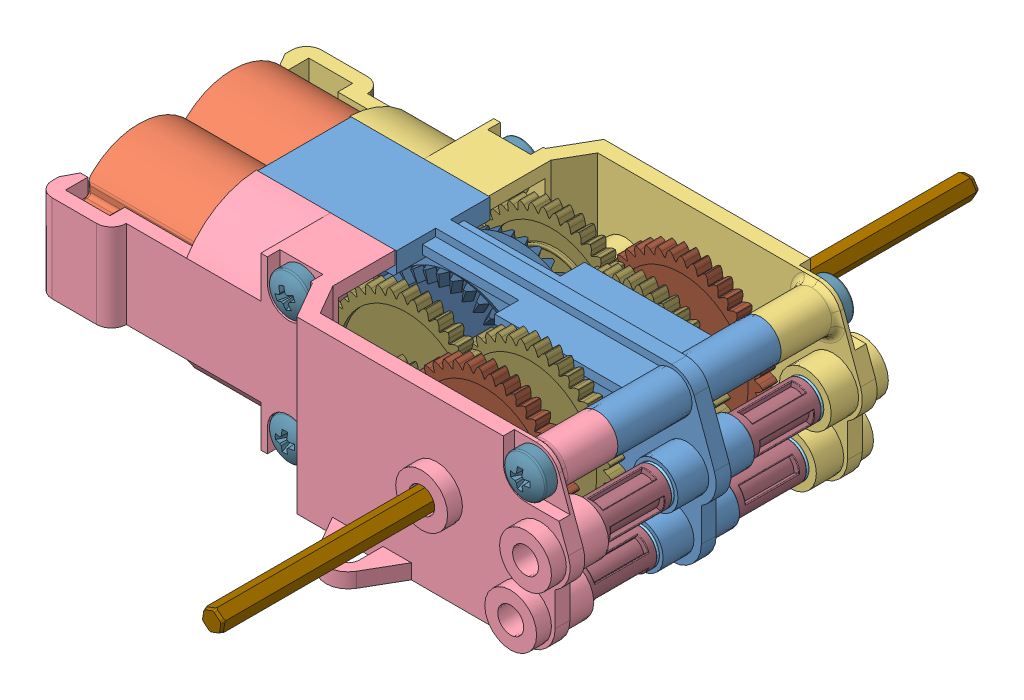
SolidWorks assembly Assem1, configuration Default. Lengths in mm.
Overall size (76.1 30.91 102).
43 component instances, 14 part files, 106 mates.
Components (placement in the parent):
- middle-1: middle [Default] at (-26.5046 -12.0507 -0.5469) size (56.5 23 25.6)
- motor-1: motor [Default] at (-17.5046 -0.5507 0.1531) x (0 -1 0) z (1 0 0) size (18 15.56 38)
- left-1: left [Default] at (-1.1076 -0.2507 -21.2469) size (73.9 23 20.6)
- right-1: right [Default] at (-1.1076 -0.2507 18.1531) size (74.8 23 20.6)
- motor-2: motor [Default] at (-17.5046 -0.5507 -1.2469) x (0 1 0) z (1 0 0) size (18 15.56 38)
- DG_brass_gap4.0-1: DG_brass_gap4.0 [Default] at (25.9954 -0.0507 14.2531) x (0.99998 -0.006331 0) z (-0.006331 -0.99998 0) size (5 3.41 5)
- DG_gold_brass-1: DG_gold_brass [Default] at (11.9954 -0.0507 13.2541) x (-0.933875 -0.357599 0) z (-0.357599 0.933875 0) size (8.08 4.5 7)
- DG_purple_8_mtr-1: DG_purple_8_mtr [Default] at (-8.0046 -0.5507 -6.8469) x (0 -0.990906 0.134553) z (0 -0.134553 -0.990906) size (5 5 5)
- DG_shaft_23mm-1: DG_shaft_23mm [Default] at (-2.0046 -0.0507 0.4531) size (3 3 17.7)
- DG_shaft_50mm-1: DG_shaft_50mm [Default] at (11.9954 -0.0507 0.4531) x (-0.776627 0.62996 0) z (0.62996 0.776627 0) size (3 50 2.6)
- DG_yellow_34_12_N01-1: DG_yellow_34_12_N01 [Default] at (-2.0046 -0.0507 2.5531) x (-0.998453 -0.055609 0) z (-0.055609 0.998453 0) size (20 6.2 20)
- TG_G3-2: TG_G3 [Default] at (11.9954 -0.0507 11.7541) x (-0.776627 0.62996 0) z (0.62996 0.776627 0) size (21.94 4 22)
- DG_purple_8_mtr-2: DG_purple_8_mtr [Default] at (-9.0046 -0.5507 5.7531) x (0 -0.429966 0.902845) z (0 -0.902845 -0.429966) size (5 5 5)
- DG_brass_gap4.0-2: DG_brass_gap4.0 [Default] at (11.9954 -0.0507 17.9531) x (0.99998 -0.006331 0) z (-0.006331 -0.99998 0) size (5 3.41 5)
- DG_brass_gap4.0-3: DG_brass_gap4.0 [Default] at (23.9954 -8.0507 14.2531) x (0.725767 -0.687941 0) z (-0.687941 -0.725767 0) size (5 3.41 5)
- DG_shaft_23mm-2: DG_shaft_23mm [Default] at (-2.0046 -0.0507 -19.2469) size (3 3 17.7)
- DG_brass_gap4.0-5: DG_brass_gap4.0 [Default] at (11.9954 -0.0507 5.9531) x (-0.915274 -0.402833 0) z (0.402833 -0.915274 0) size (5 3.41 5)
- DG_brass_gap4.0-6: DG_brass_gap4.0 [Default] at (25.9954 -0.0507 4.8031) x (-0.718236 -0.695799 0) z (0.695799 -0.718236 0) size (5 3.41 5)
- DG_brass_gap4.0-7: DG_brass_gap4.0 [Default] at (23.9954 -8.0507 4.8031) x (0.929643 0.368461 0) z (-0.368461 0.929643 0) size (5 3.41 5)
- DG_brass_gap4.0-8: DG_brass_gap4.0 [Default] at (11.9954 -0.0507 -7.0469) x (0.99998 -0.006331 0) z (-0.006331 -0.99998 0) size (5 3.41 5)
- DG_brass_gap4.0-9: DG_brass_gap4.0 [Default] at (25.9954 -0.0507 -5.8969) x (0.99998 -0.006331 0) z (-0.006331 -0.99998 0) size (5 3.41 5)
- DG_brass_gap4.0-10: DG_brass_gap4.0 [Default] at (23.9954 -8.0507 -5.8969) x (0.974044 -0.22636 0) z (-0.22636 -0.974044 0) size (5 3.41 5)
- TG_G2-1: TG_G2 [Default] at (11.9954 -0.0507 5.5541) x (-0.399469 -0.916747 0) z (-0.916747 0.399469 0) size (21.94 6.7 22)
- TG_G2-2: TG_G2 [Default] at (-2.0046 -0.0507 8.2531) x (0.970931 -0.239359 0) z (-0.239359 -0.970931 0) size (21.94 6.7 22)
- TG_G3-1: TG_G3 [Default] at (11.9954 -0.0507 -12.8479) x (1 0 0) z (0 1 0) size (21.94 4 22)
- DG_shaft_50mm-2: DG_shaft_50mm [Default] at (11.9954 -0.0507 -51.5469) x (-0.536894 0.84365 0) z (0.84365 0.536894 0) size (3 50 2.6)
- DG_yellow_34_12_N01-2: DG_yellow_34_12_N01 [Default] at (-2.0046 -0.0507 -3.6469) x (0.644274 -0.764795 0) z (0.764795 0.644274 0) size (20 6.2 20)
- TG_G2-3: TG_G2 [Default] at (-2.0046 -0.0507 -9.3469) x (-0.880396 0.47424 0) z (-0.47424 -0.880396 0) size (21.94 6.7 22)
- TG_G2-4: TG_G2 [Default] at (11.9954 -0.0507 -6.6479) x (-0.880396 0.47424 0) z (-0.47424 -0.880396 0) size (21.94 6.7 22)
- DG_gold_brass-2: DG_gold_brass [Default] at (11.9954 -0.0507 -18.8479) x (-0.5 -0.866025 0) z (-0.866025 0.5 0) size (8.08 4.5 7)
- DG_brass_gap4.0-11: DG_brass_gap4.0 [Default] at (25.9954 -0.0507 -15.3469) x (-0.718236 -0.695799 0) z (0.695799 -0.718236 0) size (5 3.41 5)
- DG_brass_gap4.0-12: DG_brass_gap4.0 [Default] at (23.9954 -8.0507 -15.3469) x (-0.718236 -0.695799 0) z (0.695799 -0.718236 0) size (5 3.41 5)
- DG_brass_gap4.0-13: DG_brass_gap4.0 [Default] at (11.9954 -0.0507 -19.0469) x (-0.718236 -0.695799 0) z (0.695799 -0.718236 0) size (5 3.41 5)
- middle pin-1: middle pin [Default] at (25.9954 -0.0507 17.1641) x (0 0 -1) z (0.982212 -0.187777 0) size (15.26 5 5)
- middle pin-3: middle pin [Default] at (23.9954 -8.0507 -2.9979) x (0 0 -1) z (-0.891557 -0.452909 0) size (15.26 5 5)
- middle pin-4: middle pin [Default] at (23.9954 -8.0507 17.1521) x (0 0 -1) z (0.709327 -0.70488 0) size (15.26 5 5)
- middle pin-6: middle pin [Default] at (25.9954 -0.0507 -2.9979) x (0 0 -1) z (0.982212 -0.187777 0) size (15.26 5 5)
- Pan Head Cross Recess Screw_DIN-1: Pan Head Cross Recess Screw_DIN [ISO 7045 - M3 x 12 - Z --- 12N] at (-12.9046 -8.9507 15.8531) x (0 0 -1) z (1 0 0) size (14.35 5.6 5.6)
- Pan Head Cross Recess Screw_DIN-2: Pan Head Cross Recess Screw_DIN [ISO 7045 - M3 x 12 - Z --- 12N] at (-12.9046 7.8493 -16.9469) x (0 0 1) z (-1 0 0) size (14.35 5.6 5.6)
- Pan Head Cross Recess Screw_DIN-3: Pan Head Cross Recess Screw_DIN [ISO 7045 - M3 x 12 - Z --- 12N] at (23.9954 7.7493 21.0531) x (0 0 -1) z (1 0 0) size (14.35 5.6 5.6)
- Pan Head Cross Recess Screw_DIN-4: Pan Head Cross Recess Screw_DIN [ISO 7045 - M3 x 12 - Z --- 12N] at (23.9954 7.7493 -22.1469) x (0 0 1) z (-1 0 0) size (14.35 5.6 5.6)
- Pan Head Cross Recess Screw_DIN-5: Pan Head Cross Recess Screw_DIN [ISO 7045 - M3 x 12 - Z --- 12N] at (-12.9046 7.8493 15.8531) x (0 0 -1) z (-0.381849 0.924225 0) size (14.35 5.6 5.6)
- Pan Head Cross Recess Screw_DIN-6: Pan Head Cross Recess Screw_DIN [ISO 7045 - M3 x 12 - Z --- 12N] at (-12.9046 -8.9507 -16.9469) x (0 0 1) z (-1 0 0) size (14.35 5.6 5.6)
Mates (geometry in assembly coordinates):
- Coincident2: coincident aligned: plane of middle-1 through (-26.5046 -12.0507 0.4531) normal (0 -1 0); plane of left-1 through (-5.6746 -12.0507 -19.2469) normal (0 -1 0)
- Concentric3: concentric aligned: cylinder of middle-1 through (29.9964 -0.5507 -6.8469) axis (-1 0 0) radius 3; cylinder of left-1 through (29.9964 -0.5507 -6.8469) axis (-1 0 0) radius 3
- Concentric4: concentric: cylinder of middle-1 through (23.9954 7.7493 0.4531) axis (0 0 -1) radius 1.35; cylinder of left-1 through (23.1217 7.7493 -19.6469) axis (0 0 -1) radius 1.35
- Concentric6: concentric aligned: cylinder of middle-1 through (23.9954 7.7493 0.4531) axis (0 0 -1) radius 1.35; cylinder of left-1 through (23.9954 7.7493 -19.2469) axis (0 0 -1) radius 1.35
- Coincident3: coincident: plane of motor-1 through (-43.9134 6.0825 -14.3969) normal (0 0 -1); plane of left-1 through (-7.984 5.3493 -14.4469) normal (0 0 1)
- Parallel1: parallel aligned: plane of motor-1 through (-44.8046 -0.5507 -6.8469) normal (-1 0 0); plane of left-1 through (-35.9076 5.3493 -14.4469) normal (-1 0 0)
- Concentric8: concentric aligned: cylinder of middle-1 through (29.9964 -0.5507 -6.8469) axis (-1 0 0) radius 3; cylinder of motor-1 through (-15.5046 -0.5507 -6.8469) axis (-1 0 0) radius 3
- Concentric9: concentric aligned: cylinder of middle-1 through (25.9954 -0.0507 0.4531) axis (0 0 -1) radius 1.75; cylinder of right-1 through (25.9954 -0.0507 20.1531) axis (0 0 -1) radius 1.75
- Concentric10: concentric aligned: cylinder of middle-1 through (11.9954 -0.0507 0.4531) axis (0 0 -1) radius 1.75; cylinder of right-1 through (11.9954 -0.0507 20.1531) axis (0 0 -1) radius 1.75
- Coincident5: coincident aligned: plane of middle-1 through (-17.5046 7.9493 0.4531) normal (-1 0 0); plane of right-1 through (-17.5046 4.5493 -33.2896) normal (-1 0 0)
- Coincident6: coincident anti-aligned: plane of middle-1 through (23.9954 7.7493 10.4531) normal (0 0 1); plane of right-1 through (23.9954 7.7493 10.4531) normal (0 0 -1)
- Coincident7: coincident anti-aligned: plane of middle-1 through (-17.5046 7.9493 0.4531) normal (-1 0 0); plane of motor-1 through (-17.5046 -0.5507 -6.8469) normal (1 0 0)
- Parallel2: parallel anti-aligned: plane of motor-1 through (-42.5046 -6.2076 0.1531) normal (0 0 1); plane of right-1 through (-7.984 5.3493 13.3531) normal (0 0 -1)
- Concentric11: concentric anti-aligned: cylinder of middle-1 through (29.9964 -0.5507 5.7531) axis (-1 0 0) radius 3; cylinder of motor-2 through (-86.933 -0.5507 5.7531) axis (1 0 0) radius 1
- Parallel3: parallel anti-aligned: plane of motor-1 through (-42.5046 -6.2076 0.1531) normal (0 0 1); plane of motor-2 through (-42.5046 5.1061 -1.2469) normal (0 0 -1)
- Coincident9: coincident aligned: plane of motor-1 through (-42.5046 -0.5507 -6.8469) normal (-1 0 0); plane of motor-2 through (-42.5046 -0.5507 5.7531) normal (-1 0 0)
- Concentric12: concentric aligned: cylinder of motor-1 through (4.1238 -0.5507 -6.8469) axis (-1 0 0) radius 1; cylinder of DG_purple_8_mtr-1 through (-8.0046 -0.5507 -6.8469) axis (-1 0 0) radius 0.75
- Coincident10: coincident aligned: plane of motor-1 through (-8.1046 -0.5507 -6.8469) normal (1 0 0); plane of DG_purple_8_mtr-1 through (-8.1046 -0.5507 -6.8469) normal (1 0 0)
- Concentric13: concentric aligned: cylinder of motor-2 through (4.1238 -0.5507 5.7531) axis (-1 0 0) radius 1; cylinder of DG_purple_8_mtr-2 through (-9.0046 -0.5507 5.7531) axis (-1 0 0) radius 0.75
- Distance1: distance = 1 mm aligned: plane of motor-2 through (-8.1046 -0.5507 5.7531) normal (1 0 0); plane of DG_purple_8_mtr-2 through (-9.1046 -0.5507 5.7531) normal (1 0 0)
- Coincident12: coincident anti-aligned: plane of right-1 through (23.9954 -8.0507 18.1531) normal (0 0 -1); plane of DG_shaft_23mm-1 through (-2.0046 -0.0507 18.1531) normal (0 0 1)
- Concentric14: concentric anti-aligned: cylinder of right-1 through (-2.0046 -0.0507 15.5031) axis (0 0 1) radius 1.5; cylinder of DG_shaft_23mm-1 through (-2.0046 -0.0507 18.1531) axis (0 0 -1) radius 1.5
- Concentric15: concentric anti-aligned: cylinder of DG_shaft_23mm-1 through (-2.0046 -0.0507 18.1531) axis (0 0 -1) radius 1.5; cylinder of DG_yellow_34_12_N01-1 through (-2.0046 -0.0507 2.5531) axis (0 0 1) radius 1.5
- Concentric16: concentric aligned: cylinder of right-1 through (25.9954 -0.0507 20.1531) axis (0 0 -1) radius 1.75; cylinder of DG_brass_gap4.0-1 through (25.9954 -0.0507 14.2531) axis (0 0 -1) radius 1.7
- Coincident13: coincident aligned: plane of right-1 through (23.9954 -8.0507 14.4531) normal (0 0 -1); circle of DG_brass_gap4.0-1
- Concentric17: concentric aligned: cylinder of right-1 through (11.9954 -0.0507 20.1531) axis (0 0 -1) radius 1.75; cylinder of DG_brass_gap4.0-2 through (11.9954 -0.0507 17.9531) axis (0 0 -1) radius 1.7
- Coincident14: coincident aligned: plane of right-1 through (23.9954 -8.0507 18.1531) normal (0 0 -1); circle of DG_brass_gap4.0-2
- Concentric18: concentric aligned: cylinder of right-1 through (23.9954 -8.0507 20.1531) axis (0 0 -1) radius 1.75; cylinder of DG_brass_gap4.0-3 through (23.9954 -8.0507 14.2531) axis (0 0 -1) radius 1.7
- Coincident15: coincident aligned: plane of right-1 through (23.9954 -8.0507 14.4531) normal (0 0 -1); circle of DG_brass_gap4.0-3
- Concentric19: concentric aligned: cylinder of middle-1 through (-2.0046 -0.0507 0.4531) axis (0 0 -1) radius 1.5; cylinder of DG_shaft_23mm-2 through (-2.0046 -0.0507 -1.5469) axis (0 0 -1) radius 1.5
- Coincident16: coincident anti-aligned: plane of middle-1 through (23.9954 -8.0507 -1.5469) normal (0 0 -1); plane of DG_shaft_23mm-2 through (-2.0046 -0.0507 -1.5469) normal (0 0 1)
- Concentric27: concentric anti-aligned: cylinder of middle-1 through (25.9954 -0.0507 0.4531) axis (0 0 -1) radius 1.75; cylinder of DG_brass_gap4.0-6 through (25.9954 -0.0507 4.8031) axis (0 0 1) radius 1.7
- Coincident20: coincident aligned: plane of middle-1 through (23.9954 -8.0507 4.6031) normal (0 0 1); circle of DG_brass_gap4.0-7
- Concentric24: concentric aligned: cylinder of middle-1 through (11.9954 -0.0507 0.4531) axis (0 0 -1) radius 1.75; cylinder of DG_brass_gap4.0-8 through (11.9954 -0.0507 -7.0469) axis (0 0 -1) radius 1.7
- Coincident21: coincident aligned: plane of middle-1 through (11.9954 -0.0507 -6.8469) normal (0 0 -1); circle of DG_brass_gap4.0-8
- Concentric25: concentric aligned: cylinder of middle-1 through (25.9954 -0.0507 0.4531) axis (0 0 -1) radius 1.75; cylinder of DG_brass_gap4.0-9 through (25.9954 -0.0507 -5.8969) axis (0 0 -1) radius 1.7
- Coincident22: coincident aligned: plane of middle-1 through (25.9954 -0.0507 -5.6969) normal (0 0 -1); circle of DG_brass_gap4.0-9
- Concentric26: concentric aligned: cylinder of middle-1 through (23.9954 -8.0507 0.4531) axis (0 0 -1) radius 1.75; cylinder of DG_brass_gap4.0-10 through (23.9954 -8.0507 -5.8969) axis (0 0 -1) radius 1.7
- Coincident23: coincident aligned: plane of middle-1 through (23.9954 -8.0507 -5.6969) normal (0 0 -1); circle of DG_brass_gap4.0-10
- Concentric28: concentric anti-aligned: cylinder of middle-1 through (23.9954 -8.0507 0.4531) axis (0 0 -1) radius 1.75; cylinder of DG_brass_gap4.0-7 through (23.9954 -8.0507 4.8031) axis (0 0 1) radius 1.7
- Concentric29: concentric anti-aligned: cylinder of middle-1 through (25.9954 -0.0507 0.4531) axis (0 0 -1) radius 1.75; cylinder of DG_brass_gap4.0-6 through (25.9954 -0.0507 4.8031) axis (0 0 1) radius 1.7
- Coincident24: coincident anti-aligned: plane of middle-1 through (25.9954 -0.0507 4.6031) normal (0 0 1); plane of DG_brass_gap4.0-6 through (24.1998 -1.7902 4.6031) normal (0 0 -1)
- Coincident25: coincident anti-aligned: plane of middle-1 through (23.9954 -8.0507 0.4531) normal (0 0 1); plane of DG_shaft_50mm-1 through (10.8305 0.8942 0.4531) normal (0 0 -1)
- Coincident26: coincident: line of DG_shaft_50mm-1 through (12.2313 1.4306 49.9071) axis (0 0 -1); cylinder of DG_brass_gap4.0-2 through (11.9954 -0.0507 17.9531) axis (0 0 -1) radius 1.5
- Concentric32: concentric anti-aligned: circle of DG_shaft_50mm-1; circle of DG_brass_gap4.0-2
- Distance2: distance = 0.1 mm anti-aligned: plane of middle-1 through (-2.0046 -0.0507 2.9531) normal (0 0 1); plane of DG_yellow_34_12_N01-1 through (-2.0046 -0.0507 3.0531) normal (0 0 -1)
- Tangent3: tangent: face of DG_brass_gap4.0-5; plane of TG_G2-1 through (30.2767 -8.0167 6.0541) normal (0 0 -1)
- Concentric33: concentric anti-aligned: cylinder of middle-1 through (11.9954 -0.0507 0.4531) axis (0 0 -1) radius 1.75; cylinder of DG_brass_gap4.0-5 through (11.9954 -0.0507 5.9531) axis (0 0 1) radius 1.7
- Coincident29: coincident anti-aligned: plane of middle-1 through (11.9954 -0.0507 5.7531) normal (0 0 1); plane of DG_brass_gap4.0-5 through (9.7072 -1.0578 5.7531) normal (0 0 -1)
- Parallel4: parallel anti-aligned: plane of middle-1 through (23.9954 -8.0507 0.4531) normal (0 0 1); plane of TG_G2-1 through (30.2767 -8.0167 6.0541) normal (0 0 -1)
- Concentric34: concentric aligned: circle of middle-1; circle of TG_G2-1
- Concentric35: concentric anti-aligned: cylinder of DG_shaft_23mm-1 through (-2.0046 -0.0507 18.1531) axis (0 0 -1) radius 1.5; cylinder of TG_G2-2 through (-2.0046 -0.0507 8.2531) axis (0 0 1) radius 1.5
- Coincident30: coincident anti-aligned: plane of DG_yellow_34_12_N01-1 through (-2.0046 -0.0507 8.7531) normal (0 0 1); plane of TG_G2-2 through (2.7686 19.311 8.7531) normal (0 0 -1)
- Coincident31: coincident anti-aligned: plane of DG_gold_brass-1 through (8.2212 -1.4959 13.2541) normal (0 0 -1); plane of TG_G3-2 through (11.9954 -0.0507 13.2541) normal (0 0 1)
- Parallel5: parallel anti-aligned: plane of DG_gold_brass-1 through (8.8567 2.4952 17.7541) normal (-0.987559 0.157248 0); plane of TG_G3-2 through (8.8567 2.4952 15.7541) normal (0.987559 -0.157248 0)
- Concentric36: concentric anti-aligned: cylinder of DG_gold_brass-1 through (11.9954 -0.0507 17.7541) axis (0 0 -1) radius 1.5; cylinder of TG_G3-2 through (11.9954 -0.0507 11.7541) axis (0 0 1) radius 1.5
- Concentric37: concentric aligned: cylinder of DG_gold_brass-1 through (11.9954 -0.0507 17.7541) axis (0 0 -1) radius 1.5; cylinder of DG_brass_gap4.0-2 through (11.9954 -0.0507 17.9531) axis (0 0 -1) radius 1.7
- Coincident34: coincident anti-aligned: plane of TG_G3-2 through (-0.5669 -15.5378 12.2541) normal (0 0 -1); plane of TG_G2-1 through (11.9954 -0.0507 12.2541) normal (0 0 1)
- Parallel6: parallel aligned: plane of DG_gold_brass-1 through (8.2212 -1.4959 17.7541) normal (-0.62996 -0.776627 0); plane of DG_shaft_50mm-1 through (10.5946 -0.5871 50.4531) normal (-0.62996 -0.776627 0)
- GearMate1: gear = 12 : 42 mm: circle of TG_G3-2; circle of TG_G2-2
- GearMate2: gear = 12 : 41 mm: circle of TG_G2-2; circle of TG_G2-1
- GearMate3: gear = 41 : 12 mm: circle of DG_yellow_34_12_N01-1; circle of TG_G2-1
- GearMate4: gear = 8 : 18 mm: circle of DG_yellow_34_12_N01-1; circle of DG_purple_8_mtr-2
- Coincident36: coincident anti-aligned: plane of middle-1 through (23.9954 -8.0507 -1.5469) normal (0 0 -1); plane of DG_shaft_50mm-2 through (11.1901 1.2148 -1.5469) normal (0 0 1)
- Concentric38: concentric aligned: circle of middle-1; circle of DG_shaft_50mm-2
- Concentric39: concentric aligned: cylinder of DG_shaft_23mm-2 through (-2.0046 -0.0507 -1.5469) axis (0 0 -1) radius 1.5; cylinder of DG_yellow_34_12_N01-2 through (-2.0046 -0.0507 -3.6469) axis (0 0 -1) radius 1.5
- Distance3: distance = 0.1 mm anti-aligned: plane of middle-1 through (-2.0046 -0.0507 -4.0469) normal (0 0 -1); plane of DG_yellow_34_12_N01-2 through (-2.0046 -0.0507 -4.1469) normal (0 0 1)
- Concentric40: concentric aligned: cylinder of DG_shaft_23mm-2 through (-2.0046 -0.0507 -1.5469) axis (0 0 -1) radius 1.5; cylinder of TG_G2-3 through (-2.0046 -0.0507 -9.3469) axis (0 0 -1) radius 1.5
- Coincident38: coincident anti-aligned: plane of DG_yellow_34_12_N01-2 through (-2.0046 -0.0507 -9.8469) normal (0 0 -1); plane of TG_G2-3 through (7.4524 17.5056 -9.8469) normal (0 0 1)
- Concentric41: concentric aligned: cylinder of middle-1 through (11.9954 -0.0507 5.7531) axis (0 0 -1) radius 3; cylinder of TG_G2-4 through (11.9954 -0.0507 -6.6479) axis (0 0 -1) radius 1.5
- Tangent4: tangent: face of DG_brass_gap4.0-8; plane of TG_G2-4 through (21.4524 17.5056 -7.1479) normal (0 0 1)
- Coincident39: coincident aligned: cylinder of TG_G3-1 through (11.9954 -0.0507 -12.8479) axis (0 0 -1) radius 1.5; circle of TG_G2-4
- Coincident40: coincident anti-aligned: plane of TG_G3-1 through (11.9954 -19.9921 -13.3479) normal (0 0 1); plane of TG_G2-4 through (11.9954 -0.0507 -13.3479) normal (0 0 -1)
- Tangent5: tangent aligned: cylinder of DG_gold_brass-2 through (11.9954 -0.0507 -14.3479) axis (0 0 -1) radius 1.5; cylinder of TG_G3-1 through (11.9954 -0.0507 -12.8479) axis (0 0 -1) radius 1.5
- Parallel7: parallel anti-aligned: plane of TG_G3-1 through (9.9747 -3.5507 -16.8479) normal (0.866025 0.5 0); plane of DG_gold_brass-2 through (7.954 -0.0507 -14.3479) normal (-0.866025 -0.5 0)
- Coincident42: coincident anti-aligned: plane of TG_G3-1 through (11.9954 -0.0507 -14.3479) normal (0 0 -1); plane of DG_gold_brass-2 through (9.9747 -3.5507 -14.3479) normal (0 0 1)
- GearMate5: gear = 38 : 8 mm: circle of DG_purple_8_mtr-1; circle of DG_yellow_34_12_N01-2
- GearMate6: gear = 41 : 12 mm: circle of DG_yellow_34_12_N01-2; circle of TG_G2-4
- GearMate7: gear = 41 : 12 mm: circle of TG_G2-4; circle of TG_G2-3
- GearMate9: gear = 42 : 12 mm: circle of TG_G2-3; circle of TG_G3-1
- Concentric42: concentric anti-aligned: cylinder of left-1 through (25.9954 -0.0507 -19.2469) axis (0 0 -1) radius 1.75; cylinder of DG_brass_gap4.0-11 through (25.9954 -0.0507 -15.3469) axis (0 0 1) radius 1.7
- Coincident43: coincident anti-aligned: plane of left-1 through (23.9954 -8.0507 -15.5469) normal (0 0 1); plane of DG_brass_gap4.0-11 through (24.1998 -1.7902 -15.5469) normal (0 0 -1)
- Concentric43: concentric anti-aligned: cylinder of left-1 through (23.9954 -8.0507 -19.2469) axis (0 0 -1) radius 1.75; cylinder of DG_brass_gap4.0-12 through (23.9954 -8.0507 -15.3469) axis (0 0 1) radius 1.7
- Coincident44: coincident anti-aligned: plane of left-1 through (23.9954 -8.0507 -15.5469) normal (0 0 1); plane of DG_brass_gap4.0-12 through (22.1998 -9.7902 -15.5469) normal (0 0 -1)
- Concentric44: concentric anti-aligned: cylinder of left-1 through (11.9954 -0.0507 -19.2469) axis (0 0 -1) radius 1.75; cylinder of DG_brass_gap4.0-13 through (11.9954 -0.0507 -19.0469) axis (0 0 1) radius 1.7
- Coincident45: coincident anti-aligned: plane of left-1 through (23.9954 -8.0507 -19.2469) normal (0 0 1); plane of DG_brass_gap4.0-13 through (10.1998 -1.7902 -19.2469) normal (0 0 -1)
- Concentric45: concentric aligned: cylinder of DG_brass_gap4.0-6 through (25.9954 -0.0507 4.8031) axis (0 0 1) radius 1.5; cylinder of middle pin-1 through (25.9954 -0.0507 17.1641) axis (0 0 1) radius 1.5
- Tangent6: tangent: face of DG_brass_gap4.0-6; plane of middle pin-1 through (23.5399 0.4187 4.9041) normal (0 0 -1)
- Concentric47: concentric aligned: cylinder of DG_brass_gap4.0-7 through (23.9954 -8.0507 4.8031) axis (0 0 1) radius 1.5; cylinder of middle pin-3 through (23.9954 -8.0507 -2.9979) axis (0 0 1) radius 1.5
- Concentric48: concentric aligned: cylinder of DG_brass_gap4.0-12 through (23.9954 -8.0507 -15.3469) axis (0 0 1) radius 1.5; cylinder of middle pin-4 through (23.9954 -8.0507 17.1521) axis (0 0 1) radius 1.5
- Tangent7: tangent: face of DG_brass_gap4.0-3; plane of middle pin-4 through (22.9314 -6.9934 14.1521) normal (0 0 1)
- Tangent8: tangent: face of DG_brass_gap4.0-10; plane of middle pin-3 through (25.3328 -7.3713 -5.9979) normal (0 0 1)
- Concentric50: concentric anti-aligned: cylinder of DG_brass_gap4.0-9 through (25.9954 -0.0507 -5.8969) axis (0 0 -1) radius 1.5; cylinder of middle pin-6 through (25.9954 -0.0507 -2.9979) axis (0 0 1) radius 1.5
- Tangent9: tangent: face of DG_brass_gap4.0-9; plane of middle pin-6 through (24.5221 0.231 -5.9979) normal (0 0 1)
- Concentric51: concentric aligned: cylinder of left-1 through (-12.9046 -8.9507 30.3958) axis (0 0 -1) radius 1.35; cylinder of Pan Head Cross Recess Screw_DIN-6 through (-12.9046 -8.9507 -42.3469) axis (0 0 -1) radius 1.5
- Concentric52: concentric aligned: cylinder of left-1 through (-12.9046 7.8493 30.3958) axis (0 0 -1) radius 1.35; cylinder of Pan Head Cross Recess Screw_DIN-2 through (-12.9046 7.8493 -42.3469) axis (0 0 -1) radius 1.5
- Concentric53: concentric aligned: cylinder of left-1 through (23.9954 7.7493 -19.2469) axis (0 0 -1) radius 1.35; cylinder of Pan Head Cross Recess Screw_DIN-4 through (23.9954 7.7493 -47.5469) axis (0 0 -1) radius 1.5
- Concentric54: concentric anti-aligned: cylinder of right-1 through (23.9954 7.7493 20.1531) axis (0 0 -1) radius 1.35; cylinder of Pan Head Cross Recess Screw_DIN-3 through (23.9954 7.7493 46.4531) axis (0 0 1) radius 1.5
- Concentric55: concentric aligned: cylinder of right-1 through (-12.9046 -8.9507 -33.2896) axis (0 0 1) radius 1.35; cylinder of Pan Head Cross Recess Screw_DIN-1 through (-12.9046 -8.9507 41.2531) axis (0 0 1) radius 1.5
- Concentric56: concentric aligned: cylinder of right-1 through (-12.9046 7.8493 -33.2896) axis (0 0 1) radius 1.35; cylinder of Pan Head Cross Recess Screw_DIN-5 through (-12.9046 7.8493 41.2531) axis (0 0 1) radius 1.5
- Coincident46: coincident anti-aligned: plane of right-1 through (23.9954 7.7493 18.6531) normal (0 0 1); plane of Pan Head Cross Recess Screw_DIN-3 through (23.9954 9.2493 18.6531) normal (0 0 -1)
- Coincident47: coincident aligned: plane of Pan Head Cross Recess Screw_DIN-1 through (-12.9046 -7.4507 13.4531) normal (0 0 -1); plane of Pan Head Cross Recess Screw_DIN-5 through (-14.2909 7.2765 13.4531) normal (0 0 -1)
- Coincident48: coincident anti-aligned: plane of right-1 through (-12.9046 -8.9507 13.4531) normal (0 0 1); plane of Pan Head Cross Recess Screw_DIN-1 through (-12.9046 -7.4507 13.4531) normal (0 0 -1)
- Coincident49: coincident anti-aligned: plane of left-1 through (-12.9046 -8.9507 -14.5469) normal (0 0 -1); plane of Pan Head Cross Recess Screw_DIN-6 through (-12.9046 -7.4507 -14.5469) normal (0 0 1)
- Coincident50: coincident aligned: plane of left-1 through (-12.9046 -8.9507 -14.5469) normal (0 0 -1); circle of Pan Head Cross Recess Screw_DIN-2
- Coincident51: coincident anti-aligned: plane of left-1 through (23.9954 7.7493 -19.7469) normal (0 0 -1); plane of Pan Head Cross Recess Screw_DIN-4 through (23.9954 9.2493 -19.7469) normal (0 0 1)
